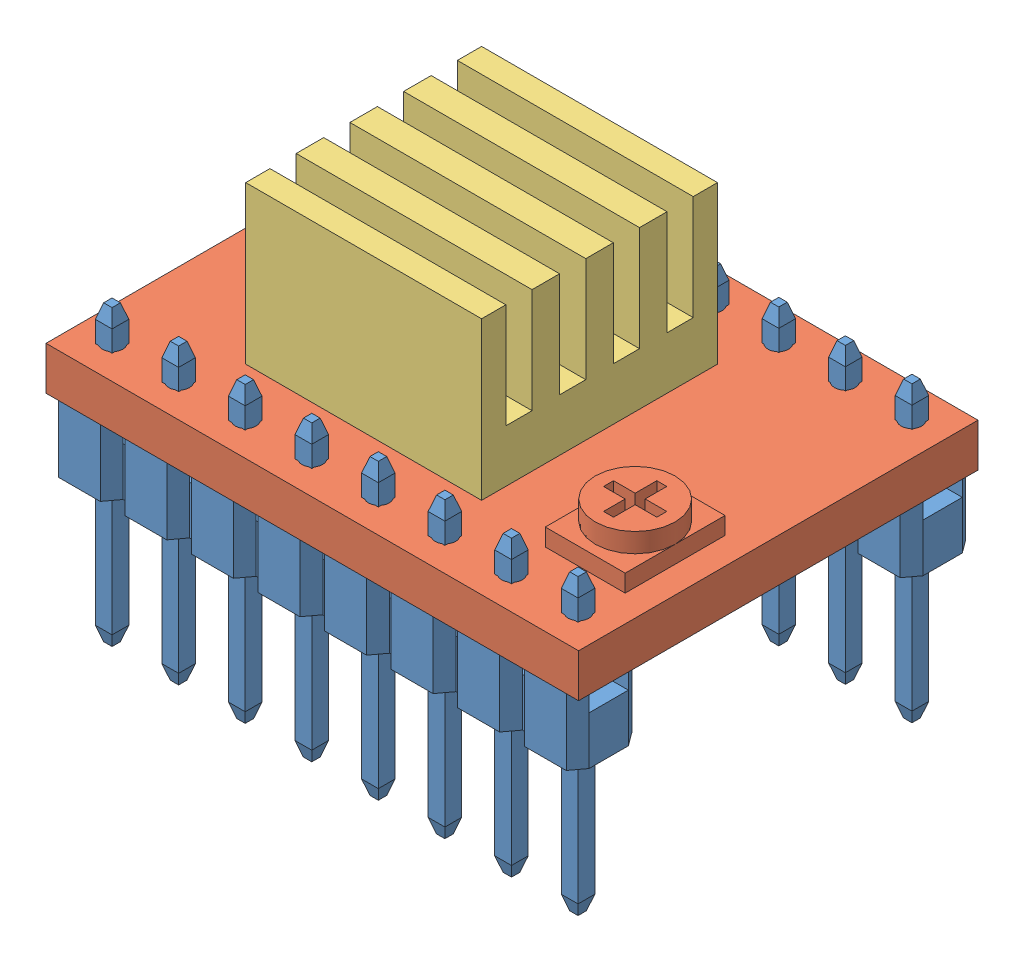
SolidWorks assembly Driver, configuration Default. Lengths in mm.
Overall size (20.32 15.85 15.24).
4 component instances, 3 part files, 0 mates.
Components (placement in the parent):
- pin_header_aw140-eg-g08d-1: pin_header_aw140-eg-g08d [Default] at (0 0 6.37) size (20.22 11.2 2.5)
- pin_header_aw140-eg-g08d-2: pin_header_aw140-eg-g08d [Default] at (0 0 -6.37) size (20.22 11.2 2.5)
- Driver_PCB-1: Driver_PCB [Default] at origin size (20.32 3.05 15.24)
- Heatsink-1: Heatsink [Default] at (-5.66 1.651 0) x (0 0 -1) z (1 0 0) size (9 6 9)
